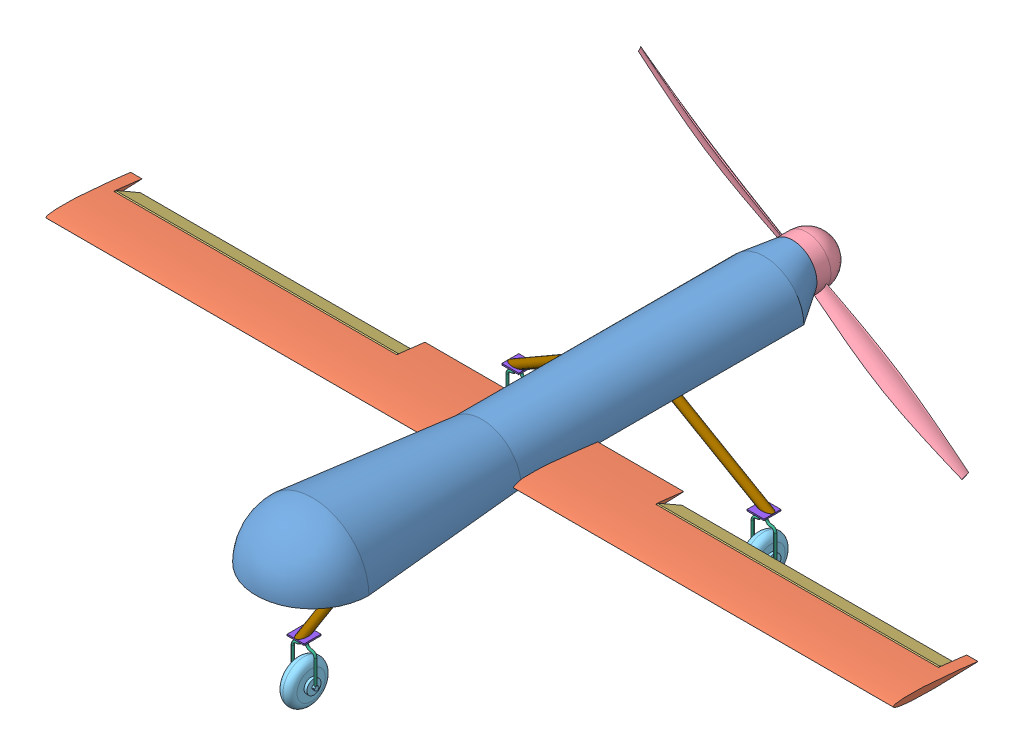
SolidWorks assembly Montaj1, configuration Varsayılan. Lengths in mm.
Overall size (1500 449.33 1017.93).
33 component instances, 9 part files, 20 mates.
Components (placement in the parent):
- bodyson-1: bodyson [Varsayılan] at (317.3834 145.5168 869.224) size (200.03 116 950.01)
- kanatveyönlendişrici-1: kanatveyönlendişrici [Varsayılan] at (176.2817 -1356.3046 478.5843) x (-1 0 0) z (0 0.999328 -0.036657) size (1500 151.05 12.08)
  - kanat-1: kanat [Varsayılan] at (-139.1018 97.9691 1505.0003) x (0 -1 0) z (1 0 0) size (151.05 12.08 1500)
- yönlendirici-1: yönlendirici [Varsayılan] at (1040.3834 138.9052 461.6812) x (-1 0 0) z (0 -0.354767 -0.934955) size (509.5 7.96 50)
- yönlendirici-2: yönlendirici [Varsayılan] at (81.3834 138.8282 461.7299) x (-1 0 0) z (0 -0.358955 -0.933355) size (509.5 7.96 50)
- pervanekanat-1: pervanekanat [Varsayılan] at (236.4249 199.4219 45.7304) x (-0.84981 0.527089 0) z (-0.527089 -0.84981 0) size (683.18 67.93 85.86)
- iniş düz-1: iniş düz [Varsayılan] at (213.4968 43.2888 836.041) x (0 0.000013 -1) z (1 0 0) size (219.34 205.85 45)
  - inişteker-1: inişteker [Varsayılan] at (-69.7476 -84.3582 38.1266) x (0 0 -1) z (1 0 0) size (45 109.55 75)
    - teker-1: teker [Varsayılan] at (-96.4188 18.2391 16.1212) size (45 75 75)
    - tekertutacağı-1: tekertutacağı [Varsayılan] at (-95.165 -24.524 16.138) x (-0.00479 0 -0.999989) z (0.999989 0 -0.00479) size (4.12 72.8 19.37)
    - tekertutacağı-2: tekertutacağı [Varsayılan] at (-47.6741 -24.5106 16.0152) x (0.0286 0 0.999591) z (-0.999591 0 0.0286) size (4.12 72.8 19.37)
    - tekermenteşe-1: tekermenteşe [Varsayılan] at (-66.7729 80.5024 16.5594) x (0 0 1) z (-1 0 0) size (11.94 4.5 4.93)
    - tekermenteşe-2: tekermenteşe [Varsayılan] at (-76.0587 80.5345 16.0473) x (0 0 -1) z (1 0 0) size (11.94 4.5 4.93)
    - sapbağlantı-2: sapbağlantı [Varsayılan] at (-71.4165 76.9961 16.185) x (0 0 -1) z (1 0 0) size (30 7.5 30)
  - Parça1-1: Parça1 [Varsayılan] at (-16.5332 35.0589 109.2187) size (196.8 96.3 15)
- tekermontajj-4: tekermontajj [Varsayılan] at (409.8593 28.939 260.5149) x (1 -0.000013 0) z (0 0 1) size (204.32 205.85 75)
  - inişteker-1: inişteker [Varsayılan] at (200.3625 -70.0075 14.5577) size (45 109.55 75)
    - teker-1: teker [Varsayılan] at (-96.4188 18.2391 16.1212) size (45 75 75)
    - tekertutacağı-1: tekertutacağı [Varsayılan] at (-95.165 -24.524 16.138) x (-0.00479 0 -0.999989) z (0.999989 0 -0.00479) size (4.12 72.8 19.37)
    - tekertutacağı-2: tekertutacağı [Varsayılan] at (-47.6741 -24.5106 16.0152) x (0.0286 0 0.999591) z (-0.999591 0 0.0286) size (4.12 72.8 19.37)
    - tekermenteşe-1: tekermenteşe [Varsayılan] at (-66.7729 80.5024 16.5594) x (0 0 1) z (-1 0 0) size (11.94 4.5 4.93)
    - tekermenteşe-2: tekermenteşe [Varsayılan] at (-76.0587 80.5345 16.0473) x (0 0 -1) z (1 0 0) size (11.94 4.5 4.93)
    - sapbağlantı-2: sapbağlantı [Varsayılan] at (-71.4165 76.9961 16.185) x (0 0 -1) z (1 0 0) size (30 7.5 30)
  - Parça1-4: Parça1 [Varsayılan] at (91.8763 49.4096 27.7271) x (-1 0 0) z (0 0 -1) size (196.8 96.3 15)
- tekermontajj-5: tekermontajj [Varsayılan] at (226.8937 28.939 315.2464) x (-1 -0.000013 0) z (0 0 -1) size (204.32 205.85 75)
  - inişteker-1: inişteker [Varsayılan] at (200.3625 -70.0075 14.5577) size (45 109.55 75)
    - teker-1: teker [Varsayılan] at (-96.4188 18.2391 16.1212) size (45 75 75)
    - tekertutacağı-1: tekertutacağı [Varsayılan] at (-95.165 -24.524 16.138) x (-0.00479 0 -0.999989) z (0.999989 0 -0.00479) size (4.12 72.8 19.37)
    - tekertutacağı-2: tekertutacağı [Varsayılan] at (-47.6741 -24.5106 16.0152) x (0.0286 0 0.999591) z (-0.999591 0 0.0286) size (4.12 72.8 19.37)
    - tekermenteşe-1: tekermenteşe [Varsayılan] at (-66.7729 80.5024 16.5594) x (0 0 1) z (-1 0 0) size (11.94 4.5 4.93)
    - tekermenteşe-2: tekermenteşe [Varsayılan] at (-76.0587 80.5345 16.0473) x (0 0 -1) z (1 0 0) size (11.94 4.5 4.93)
    - sapbağlantı-2: sapbağlantı [Varsayılan] at (-71.4165 76.9961 16.185) x (0 0 -1) z (1 0 0) size (30 7.5 30)
  - Parça1-4: Parça1 [Varsayılan] at (91.8763 49.4096 27.7271) x (-1 0 0) z (0 0 -1) size (196.8 96.3 15)
Mates (geometry in assembly coordinates):
- Çakışık1: coincident: plane of bodyson-1 through (385.3834 145.5168 869.224) normal (1 0 0); plane of kanatveyönlendişrici-1/kanat-1 through (385.3834 162.5997 420.8362) normal (-1 0 0)
- Teğet11: tangent: line of bodyson-1 through (385.3834 145.5168 569.224) axis (0 0 -1); curve of kanatveyönlendişrici-1/kanat-1
- Kilitle2: lock: unknown of bodyson-1; unknown of kanatveyönlendişrici-1/kanat-1
- Eş Merkezli3: concentric: cylinder of kanatveyönlendişrici-1/kanat-1 through (534.3834 149.7217 478.9683) axis (1 0 0) radius 2.5; cylinder of yönlendirici-1 through (535.8834 149.7217 478.9683) axis (1 0 0) radius 2.5
- Eş Merkezli4: concentric: cylinder of kanatveyönlendişrici-1/kanat-1 through (1045.3834 149.7217 478.9683) axis (-1 0 0) radius 2.5; cylinder of yönlendirici-1 through (1045.3834 149.7217 478.9683) axis (-1 0 0) radius 2.5
- Çakışık2: coincident: circle of kanatveyönlendişrici-1/kanat-1; circle of yönlendirici-1
- Eş Merkezli5: concentric: cylinder of kanatveyönlendişrici-1/kanat-1 through (-424.6166 149.7217 478.9683) axis (1 0 0) radius 2.5; cylinder of yönlendirici-2 through (-423.1166 149.722 478.9683) axis (1 0 0) radius 2.5
- Eş Merkezli6: concentric: cylinder of kanatveyönlendişrici-1/kanat-1 through (86.3834 149.722 478.9683) axis (-1 0 0) radius 2.5; cylinder of yönlendirici-2 through (86.3834 149.722 478.9683) axis (-1 0 0) radius 2.5
- Çakışık3: coincident: circle of kanatveyönlendişrici-1/kanat-1; circle of yönlendirici-2
- Çakışık4: coincident: plane of bodyson-1 through (317.5854 172.4691 19.224) normal (0 0 -1); plane of pervanekanat-1 through (317.5854 172.4691 19.224) normal (0 0 1)
- Eş Merkezli7: concentric: circle of bodyson-1; circle of pervanekanat-1
- Paralel1: parallel: plane of bodyson-1 through (317.3834 145.5168 869.224) normal (0 -1 0); plane of iniş düz-1/Parça1-1 through (311.2154 145.5168 737.8252) normal (0 1 0)
- Çakışık10: coincident: plane of bodyson-1 through (317.3834 145.5168 869.224) normal (0 -1 0); plane of iniş düz-1/Parça1-1 through (311.2154 145.5168 737.8252) normal (0 1 0)
- Kilitle6: lock: unknown of bodyson-1; unknown of iniş düz-1/Parça1-1
- Paralel2: parallel: plane of bodyson-1 through (317.3834 145.5168 869.224) normal (0 -1 0); plane of tekermontajj-4/Parça1-4 through (386.9869 145.5168 299.7421) normal (0 1 0)
- Teğet16: tangent: plane of bodyson-1 through (317.3834 145.5168 869.224) normal (0 -1 0); curve of tekermontajj-4/Parça1-4
- Kilitle7: lock: unknown of bodyson-1; unknown of tekermontajj-4/Parça1-4
- Paralel4: parallel: plane of bodyson-1 through (317.3834 145.5168 869.224) normal (0 -1 0); plane of tekermontajj-5/Parça1-4 through (249.7662 145.5168 276.0192) normal (0 1 0)
- Çakışık13: coincident: plane of bodyson-1 through (317.3834 145.5168 869.224) normal (0 -1 0); plane of tekermontajj-5/Parça1-4 through (249.7662 145.5168 276.0192) normal (0 1 0)
- Kilitle8: lock: unknown of bodyson-1; unknown of tekermontajj-5/Parça1-4
